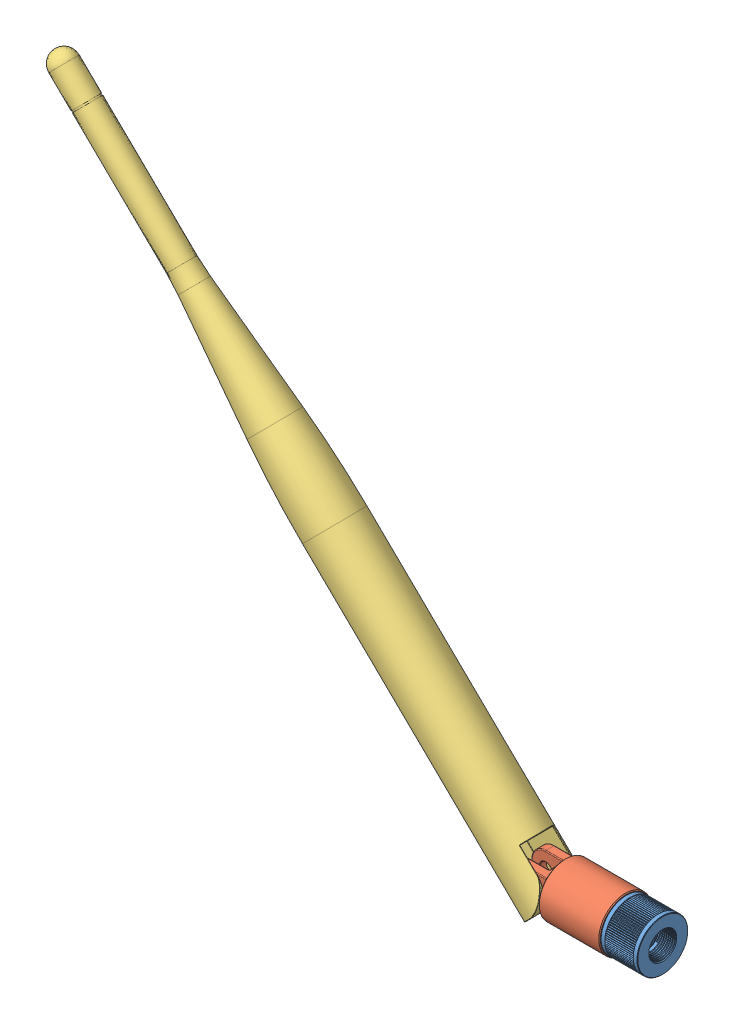
SolidWorks assembly Antenna 900MHz 3dBi Dipole (RPSMA), configuration Default. Lengths in mm.
Overall size (152.41 131.16 15.04).
3 component instances, 3 part files, 3 mates.
Components (placement in the parent):
- RPSMA (F) Connector-1: RPSMA (F) Connector [Default] at (-29.466 3.3815 10.8769) size (9.19 12.45 12.45)
- 90deg Flex Shoulder-1: 90deg Flex Shoulder [Default] at (-44.466 3.3815 10.8769) x (1 0 0) z (0 -0.999918 -0.012788) size (25 13 13)
- 900MHz Antenna Body-1: 900MHz Antenna Body [Default] at (-46.4651 -0.6724 10.825) x (0 -0.012788 0.999918) z (-0.707107 -0.707049 -0.009042) size (13.37 172.26 13)
Mates (geometry in assembly coordinates):
- Concentric1: concentric aligned: cylinder of RPSMA (F) Connector-1 through (-29.466 3.3815 10.8769) axis (-1 0 0) radius 6.225; cylinder of 90deg Flex Shoulder-1 through (-44.466 3.3815 10.8769) axis (-1 0 0) radius 6.5
- Coincident1: coincident anti-aligned: plane of RPSMA (F) Connector-1 through (-29.466 6.6065 10.8769) normal (-1 0 0); plane of 90deg Flex Shoulder-1 through (-29.466 3.2984 17.3763) normal (1 0 0)
- Hinge4: hinge = 0.785398 rad anti-aligned: cylinder of 900MHz Antenna Body-1 through (-50.966 3.4199 7.8771) axis (0 0.012788 -0.999918) radius 0.9991; cylinder of 900MHz Antenna Body-1 through (-50.966 3.2984 17.3763) axis (0 0.012788 -0.999918) radius 1.5; plane of 90deg Flex Shoulder-1 through (-57.7788 4.9328 14.897) normal (0 0.012788 -0.999918); plane of 90deg Flex Shoulder-1 through (-54.466 7.3301 14.9277) normal (0 -0.012788 0.999918); plane of 900MHz Antenna Body-1 through (-57.7788 5.0351 6.8977) normal (0.707107 0.707049 0.009042); plane of 90deg Flex Shoulder-1 through (-54.466 7.4324 6.9283) normal (0 0.999918 0.012788)
